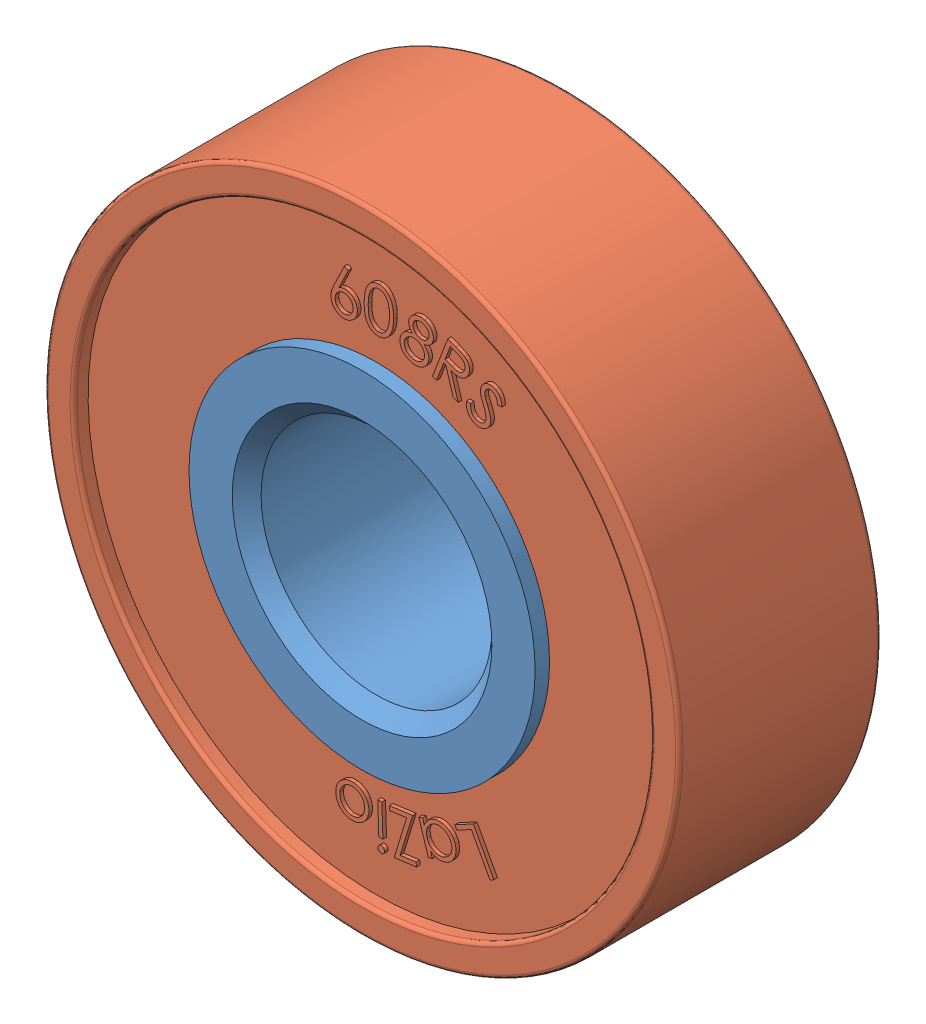
SolidWorks assembly Bearing__Type-1, configuration Default. Lengths in mm.
Overall size (25.78 25.78 7).
2 component instances, 2 part files, 1 mates.
Components (placement in the parent):
- Bearing__Type-1__Inner-1: Bearing__Type-1__Inner [Default] at (6.0462 6.0629 8.5196) size (12 12 7)
- Bearing__Type-1__Outer-1: Bearing__Type-1__Outer [Default] at (6.0462 6.0629 8.5196) x (0 0 1) z (0.190147 0.981756 0) size (7 22 22)
Mates (geometry in assembly coordinates):
- Concentric1: concentric aligned: cylinder of Bearing__Inner__Ring-1 through (6.0462 6.0629 12.0196) axis (0 0 -1) radius 6; cylinder of Bearing__Outer__Ring-1 through (6.0462 6.0629 11.5196) axis (0 0 -1) radius 6
